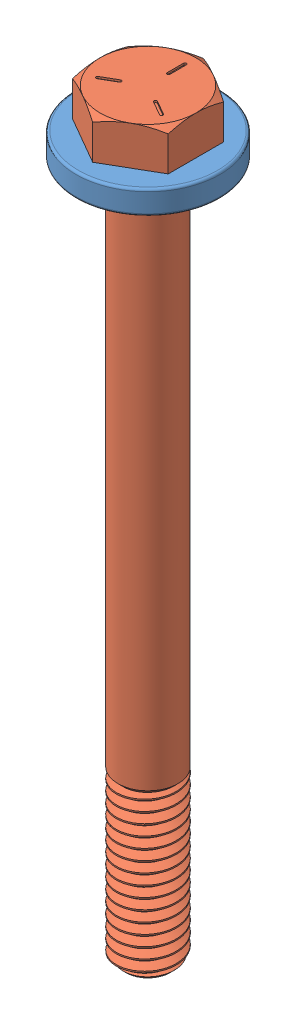
SolidWorks assembly t_slot_triplelong_screw, configuration Default. Lengths in mm.
Overall size (19.05 100.93 19.05).
2 component instances, 2 part files, 6 mates.
Components (placement in the parent):
- 5-16x.75 oversize washer 91525A326_316 Stainless Steel Washer-1: 5-16x.75 oversize washer 91525A326_316 Stainless Steel Washer [91525A326] at (0 1.5875 0) x (1 0 0) z (0 -1 0) size (19.05 19.05 3.17)
- 5s16p18x3.75 bolt 91247A598_Medium-Strength Grade 5 Steel Hex Head Screw-1: 5s16p18x3.75 bolt 91247A598_Medium-Strength Grade 5 Steel Hex Head Screw [91247A598] at (0 -41.8703 0) x (0 -1 0) z (-0.5 0 0.866025) size (100.93 14.66 12.7)
Mates (geometry in assembly coordinates):
- Concentric3: concentric anti-aligned: cylinder of 5-16x.75 oversize washer 91525A326_316 Stainless Steel Washer-1 through (0 3.175 0) axis (0 -1 0) radius 4.3688
- Coincident1: coincident anti-aligned: plane of 5-16x.75 oversize washer 91525A326_316 Stainless Steel Washer-1 through (0 0 0) normal (0 -1 0)
- Coincident4: coincident aligned: plane of 5-16x.75 oversize washer 91525A326_316 Stainless Steel Washer-1 through (0 1.5875 0) normal (1 0 0)
- Concentric5: concentric aligned: cylinder of 5-16x.75 oversize washer 91525A326_316 Stainless Steel Washer-1 through (0 3.175 0) axis (0 -1 0) radius 4.3688; cylinder of 5s16p18x3.75 bolt 91247A598_Medium-Strength Grade 5 Steel Hex Head Screw-1 through (0 3.175 0) axis (0 -1 0) radius 3.9688
- Coincident7: coincident anti-aligned: plane of 5-16x.75 oversize washer 91525A326_316 Stainless Steel Washer-1 through (0 3.175 0) normal (0 1 0); plane of 5s16p18x3.75 bolt 91247A598_Medium-Strength Grade 5 Steel Hex Head Screw-1 through (0 3.175 7.3323) normal (0 -1 0)
- Parallel2: parallel aligned: plane of 5s16p18x3.75 bolt 91247A598_Medium-Strength Grade 5 Steel Hex Head Screw-1 through (6.35 8.3344 3.6662) normal (1 0 0)
